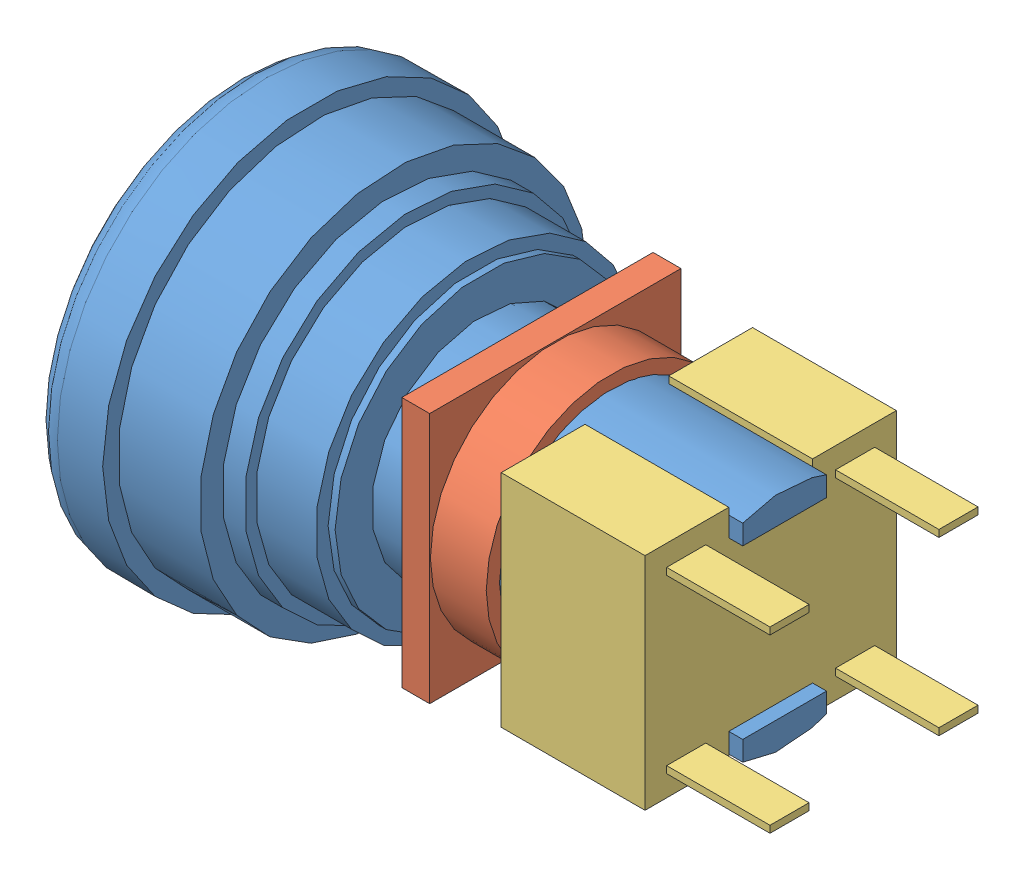
SolidWorks assembly A165E, configuration S. Lengths in mm.
Overall size (48.5 30 30).
4 component instances, 4 part files, 9 mates.
Components (placement in the parent):
- Base^A165E-1: Base^A165E [Default] at origin size (42.1 30 30) (virtual)
- Nut^A165E-1: Nut^A165E [Default] at (3.175 0 0) size (6 18 18) (virtual)
- Switch^A165E-1: Switch^A165E [Default] at (10.3 0 0) size (23.7 15.8 18) (virtual)
- Copy of A165E_M_03U_BASE^A165E-1: Copy of A165E_M_03U_BASE^A165E [Default] at origin (suppressed, hidden, virtual)
Mates (geometry in assembly coordinates):
- Concentric2: concentric anti-aligned: cylinder of Base^A165E-1 through (0 0 0) axis (1 0 0) radius 8; cylinder of Nut^A165E-1 through (9.175 0 0) axis (-1 0 0) radius 8
- Coincident3: coincident aligned: plane of Base^A165E-1 through (0 0 0) normal (0 0 1); plane of Nut^A165E-1 through (3.175 0 0) normal (0 0 1)
- Coincident4: coincident: plane of Base^A165E-1 through (0 10.6 0) normal (1 0 0); plane of Nut^A165E-1 through (3.175 -9 9) normal (-1 0 0)
- Concentric3: concentric aligned: cylinder of Base^A165E-1 through (-4.7 0 0) axis (1 0 0) radius 4.25; cylinder of Switch^A165E-1 through (4.3 0 0) axis (1 0 0) radius 4
- Coincident5: coincident anti-aligned: plane of Base^A165E-1 through (10.3 0 0) normal (1 0 0); plane of Switch^A165E-1 through (10.3 -7.9 9) normal (-1 0 0)
- Distance1: distance = 3.175 mm anti-aligned: plane of Base^A165E-1 through (0 10.6 0) normal (1 0 0); plane of Nut^A165E-1 through (3.175 -9 9) normal (-1 0 0)
- Coincident6: coincident: plane of Copy of A165E_M_03U_BASE^A165E-1 through (0 0 0) normal (0 0 1); plane of assembly through (0 0 0) normal (0 0 1)
- Concentric4: concentric aligned: cylinder of Base^A165E-1 through (0 0 0) axis (1 0 0) radius 13.9; cylinder of Copy of A165E_M_03U_BASE^A165E-1 through (0 0 0) axis (1 0 0) radius 13.9
- Coincident7: coincident aligned: plane of Base^A165E-1 through (-6.4 13.9 0) normal (1 0 0); plane of Copy of A165E_M_03U_BASE^A165E-1 through (-6.4 13.9 0) normal (1 0 0)
